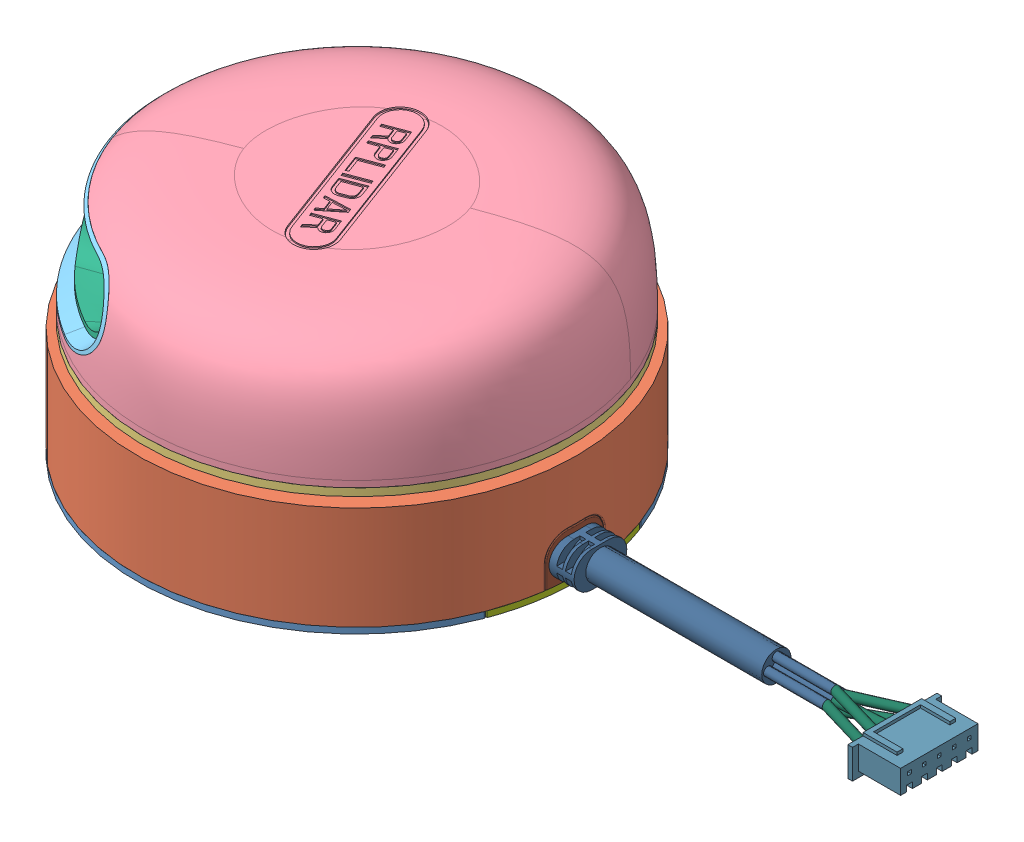
SolidWorks assembly rplidar, configuration Défaut. Lengths in mm.
Overall size (149.2 40.81 94.01).
17 component instances, 15 part files, 0 mates.
Components (placement in the parent):
- RPLIDAR A2-1: RPLIDAR A2 [Défaut] at origin size (149.2 40.81 94.01)
  - µ×¸Ç-1: µ×¸Ç [Défaut] at (-6.0269 8.2139 75) size (72.54 3.5 75)
  - ±àÂë³ÝÍâ¿Ç-1: ±àÂë³ÝÍâ¿Ç [Défaut] at (-6.0269 21.5139 75) size (75 18.2 75)
  - Ðý×ªÆ½Ì¨-1: Ðý×ªÆ½Ì¨ [Défaut] at (-6.0269 28.0139 75) x (-0.350209 0 -0.936671) z (0.936671 0 -0.350209) size (72.5 4.01 72.5)
  - LENS_1.6-1: LENS_1.6 [Défaut] at (-6.0269 21.5139 75) x (0.350209 0 0.936671) z (-0.936671 0 0.350209) size (72.5 20.11 74.54)
  - KEY_1.6-1: KEY_1.6 [Défaut] at (-6.0269 21.5139 75) x (0.350209 0 0.936671) z (-0.936671 0 0.350209) size (60.14 14.27 29.34)
  - BAT_COVER_19-1: BAT_COVER_19 [Défaut] at (-6.0269 21.5139 75) x (0.350209 0 0.936671) z (-0.936671 0 0.350209) size (56.56 17.71 24.64)
  - ·â¸Ç-1: ·â¸Ç [Défaut] at (-6.0269 9.7139 75) x (0 0 -1) z (-1 0 0) size (26 1.5 12.5)
  - ¼¤¹â·¢ÉäÍ·-1: ¼¤¹â·¢ÉäÍ· [Défaut] at (-8.2841 39.0139 48.9161) x (0.148651 0.950235 0.273781) z (-0.878816 0 0.477161) size (6 6 21.2)
  - ¾µÍ·-1: ¾µÍ· [Défaut] at (-10.3767 39.0139 94.7757) x (0.331722 0.320609 0.887226) z (-0.936671 0 0.350209) size (14 14 11.5)
  - Íâ½ÓÏßÕûÌå-1: Íâ½ÓÏßÕûÌå [Défaut] at (63.3713 -12.8505 75) size (86.12 10.5 15.7)
    - 4pinÏßÀÂ-1: 4pinÏßÀÂ [Défaut] at (-33.3982 25.5643 0) size (47.5 6 9)
    - ½ÓÏß¶Ë¸Ç-1: ½ÓÏß¶Ë¸Ç [Défaut] at (-69.3982 22.0643 0) x (0 0 1) z (-1 0 0) size (15 10.5 3.83)
    - 6p ²åÍ·-1: 6p ²åÍ· [Défaut] at (-51.3982 24.9643 0) x (0 0 1) z (-1 0 0) size (13.7 5 6.45)
    - Áã¼þ4^Íâ½ÓÏßÕûÌå-1: Áã¼þ4^Íâ½ÓÏßÕûÌå [Défaut] at (-35.3982 25.5643 0) x (0 0 1) z (-1 0 0) size (11.49 4.16 15)
    - 5pin 2.54²åÍ·-1: 5pin 2.54²åÍ· [Défaut] at (22.0731 25.0643 -0.6) x (1 0 0) z (0 0 -1) size (8 5.5 15.2)
    - Áã¼þ1^Íâ½ÓÏßÕûÌå-1: Áã¼þ1^Íâ½ÓÏßÕûÌå [Défaut] at (22.0731 25.0643 -0.6) x (0 0 -1) z (-1 0 0) size (11.69 4.45 9.97)
